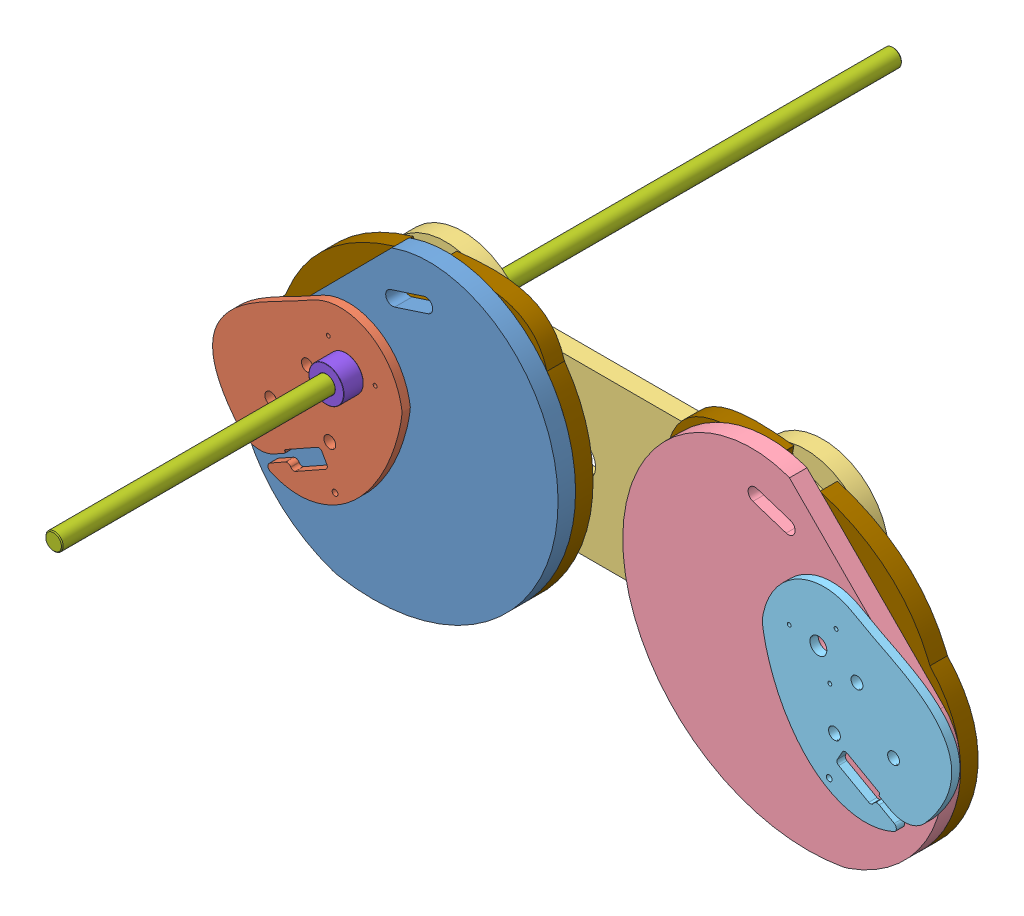
SolidWorks assembly cam_assembly_sandbox, configuration Default. Lengths in mm.
Overall size (274.02 128.99 304.8).
10 component instances, 9 part files, 22 mates.
Components (placement in the parent):
- outer_cam_sandbox-1: outer_cam_sandbox [Default] at (-85.725 0 12.7) x (0.995079 -0.099087 0) z (0 0 1) size (114.45 118.23 6.35)
- inner_cam-1: inner_cam [Default] at (-85.725 0 17.375) x (0.995079 -0.099087 0) z (0 0 1) size (67.19 67.93 3)
- cam_backing-1: cam_backing [Default] at origin size (190.95 87.41 6.35)
- Mirrorouter_cam-2: Mirrorouter_cam [Default] at (85.725 0 12.7) x (-0.995079 -0.099087 0) z (0 0 -1) size (114.45 118.23 6.35)
- Mirrorinner_cam-3: Mirrorinner_cam [Default] at (85.725 0 17.375) x (-0.995079 -0.099087 0) z (0 0 -1) size (67.19 67.93 3)
- 57155K323_Stainless Steel Ball Bearing-1: 57155K323_Stainless Steel Ball Bearing [57155K323] at (-85.725 0 14.7638) x (0.923728 0.383049 0) z (0 0 -1) size (13.89 13.89 4.76)
- 8632T139_D-Profile Rotary Shaft-1: 8632T139_D-Profile Rotary Shaft [8632T139] at (-85.725 0 -27.4279) x (0 1 0) z (0 0 1) size (6.35 5.92 304.8)
- 9414T6_Set Screw Shaft Collar-1: 9414T6_Set Screw Shaft Collar [9414T6] at (-85.725 0 22.4469) x (0 1 0) z (0 0 1) size (12.7 12.7 7.14)
- outer_cam_sandbox_profile_2-1: outer_cam_sandbox_profile_2 [Default] at (-85.725 0 6.35) x (0.995079 -0.099087 0) z (0 0 1) size (114.47 117.02 6.35)
- outer_cam_sandbox_profile_2-2: outer_cam_sandbox_profile_2 [Default] at (85.725 0 6.35) x (-0.995079 -0.099087 0) z (0 0 -1) size (114.47 117.02 6.35)
Mates (geometry in assembly coordinates):
- Coincident1: coincident aligned: plane of outer_cam-1 through (-85.725 0 12.7) normal (0.099087 0.995079 0); plane of inner_cam-1 through (-85.725 0 17.375) normal (0.099087 0.995079 0)
- Coincident2: coincident aligned: plane of outer_cam-1 through (-85.725 0 12.7) normal (0.099087 0.995079 0); plane of inner_cam-1 through (-85.725 0 17.375) normal (0.099087 0.995079 0)
- Parallel4: parallel aligned: plane of outer_cam-1 through (-85.725 0 12.7) normal (0.995079 -0.099087 0); plane of inner_cam-1 through (-85.725 0 17.375) normal (0.995079 -0.099087 0)
- Coincident5: coincident aligned: plane of cam_backing-1 through (0 0 0) normal (0 0 1)
- Coincident6: coincident aligned: plane of cam_backing-1 through (0 0 0) normal (0 1 0)
- Coincident7: coincident aligned: plane of cam_backing-1 through (0 0 0) normal (1 0 0)
- Concentric2: concentric aligned: cylinder of outer_cam-1 through (-85.725 0 15.875) axis (0 0 -1) radius 6.35; cylinder of 8632T139_D-Profile Rotary Shaft-1 through (-85.725 0 124.9721) axis (0 0 -1) radius 3.175
- Concentric3: concentric anti-aligned: circle of 8632T139_D-Profile Rotary Shaft-1; circle of cam_backing-1
- Concentric4: concentric aligned: cylinder of 8632T139_D-Profile Rotary Shaft-1 through (-85.725 0 124.9721) axis (0 0 -1) radius 3.175; cylinder of 9414T6_Set Screw Shaft Collar-1 through (-85.725 0 26.0188) axis (0 0 -1) radius 3.175
- Concentric5: concentric anti-aligned: cylinder of 8632T139_D-Profile Rotary Shaft-1 through (-85.725 0 124.9721) axis (0 0 -1) radius 3.175; cylinder of 57155K323_Stainless Steel Ball Bearing-1 through (-85.725 0 17.145) axis (0 0 1) radius 6.9469
- Parallel5: parallel aligned: plane of 8632T139_D-Profile Rotary Shaft-1 through (-88.4746 -1.5875 -179.8279) normal (-1 0 0); plane of 9414T6_Set Screw Shaft Collar-1 through (-92.075 0 22.4469) normal (-1 0 0)
- Parallel6: parallel anti-aligned: plane of 8632T139_D-Profile Rotary Shaft-1 through (-88.4746 -1.5875 -179.8279) normal (-1 0 0)
- Concentric6: concentric aligned: cylinder of inner_cam-1 through (-85.725 0 18.875) axis (0 0 -1) radius 3.075; cylinder of 8632T139_D-Profile Rotary Shaft-1 through (-85.725 0 124.9721) axis (0 0 -1) radius 3.175
- Parallel7: parallel aligned: plane of outer_cam-1; plane of cam_backing-1 through (-73.7612 27.9048 3.175) normal (-0.402465 0.915435 0)
- Concentric8: concentric aligned: cylinder of outer_cam-1 through (-63.1413 35.3047 10.8106) axis (0 0 -1) radius 2.5; cylinder of cam_backing-1 through (-63.1413 35.3047 3.175) axis (0 0 -1) radius 2.5
- Coincident29: coincident anti-aligned: plane of outer_cam-1 through (-85.725 0 15.875) normal (0 0 1); plane of 57155K323_Stainless Steel Ball Bearing-1 through (-83.7671 -4.7215 15.875) normal (0 0 -1)
- Coincident30: coincident anti-aligned: plane of inner_cam-1 through (-132.6132 -23.4107 18.875) normal (0 0 1); plane of 9414T6_Set Screw Shaft Collar-1 through (-85.725 0 18.875) normal (0 0 -1)
- Coincident31: coincident anti-aligned: plane of outer_cam_sandbox-1 through (-85.725 0 15.875) normal (0 0 1); plane of inner_cam-1 through (-132.6132 -23.4107 15.875) normal (0 0 -1)
- Coincident32: coincident aligned: plane of outer_cam_sandbox-1 through (-92.1318 19.7151 15.875) normal (-0.309058 0.951043 0); plane of outer_cam_sandbox_profile_2-1 through (-92.1318 19.7151 9.525) normal (-0.309058 0.951043 0)
- Coincident33: coincident anti-aligned: plane of outer_cam_sandbox-1 through (-85.725 0 9.525) normal (0 0 -1); plane of outer_cam_sandbox_profile_2-1 through (-85.725 0 9.525) normal (0 0 1)
- Concentric9: concentric aligned: cylinder of outer_cam_sandbox-1 through (-85.725 0 15.875) axis (0 0 -1) radius 6.35; cylinder of outer_cam_sandbox_profile_2-1 through (-85.725 0 9.525) axis (0 0 -1) radius 6.35
- Coincident34: coincident anti-aligned: plane of cam_backing-1 through (0 0 3.175) normal (0 0 1); plane of outer_cam_sandbox_profile_2-1 through (-85.725 0 3.175) normal (0 0 -1)
